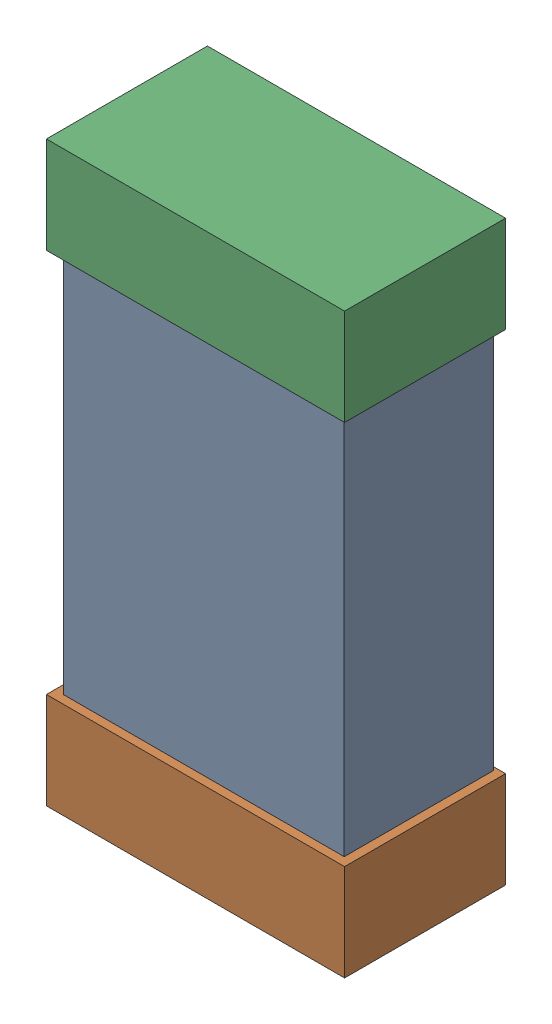
SolidWorks assembly C20, configuration Default. Lengths in mm.
Overall size (0.85 1.65 0.46).
6 component instances, 2 part files, 0 mates.
Components (placement in the parent):
- 432124816_1-1: 432124816_1 [Default] at (41.5501 30.4001 -0.8615) size (0.8 1.5 0.42)
  - Extruded (1)-1: Extruded (1) [Default] at origin size (0.8 1.5 0.42)
- 432138512_2-1: 432138512_2 [Default] at (41.5501 29.7143 -0.8715) size (0.85 0.28 0.46)
  - Extruded-1: Extruded [Default] at origin size (0.85 0.28 0.46)
- 432138512_3-1: 432138512_3 [Default] at (41.5501 31.0858 -0.8715) size (0.85 0.28 0.46)
  - Extruded-1: Extruded [Default] at origin size (0.85 0.28 0.46)
